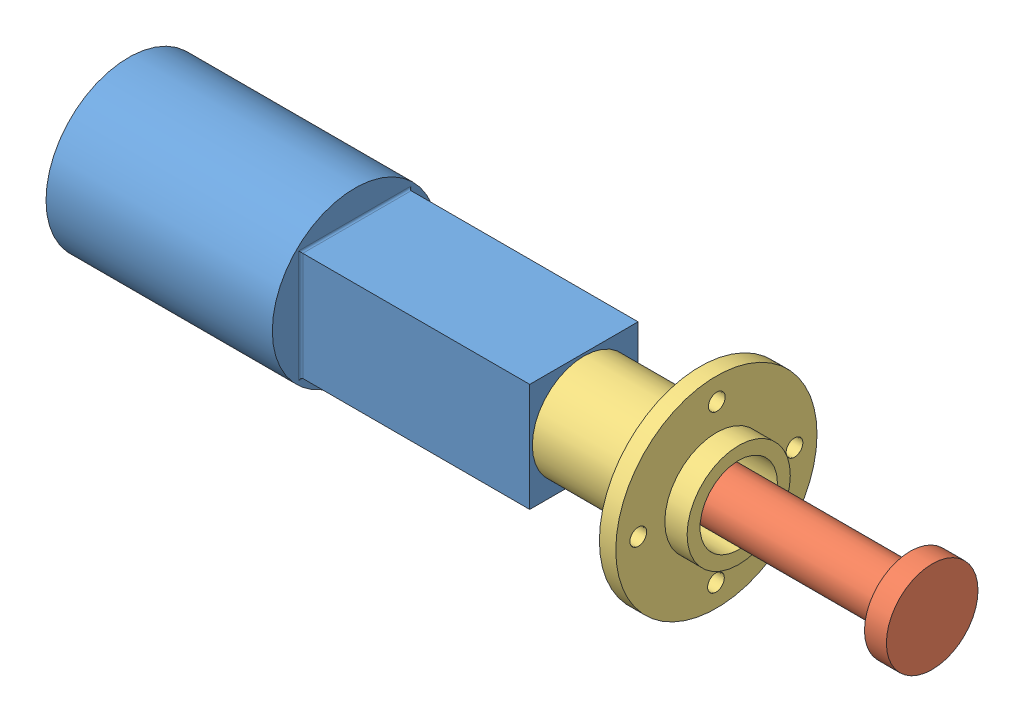
SolidWorks assembly assemblage_moteur_pla_simplifie, configuration Default. Lengths in mm.
Overall size (311.5 78.45 78.45).
3 component instances, 3 part files, 0 mates.
Components (placement in the parent):
- moteur_pla_simplifie-2: moteur_pla_simplifie [Default] at (-156.9384 51.1827 137.4238) size (176.5 64 64)
- moteur_axe_pla_simplifie-1: moteur_axe_pla_simplifie [Default] at (3.5616 51.1827 137.4238) size (151 35.5 35.5)
- front_housing_moteur_pla_simplifie-2: front_housing_moteur_pla_simplifie [Default] at (64.5616 51.1827 137.4238) x (1 0 0) z (0 0.00581 0.999983) size (60 78 78)
